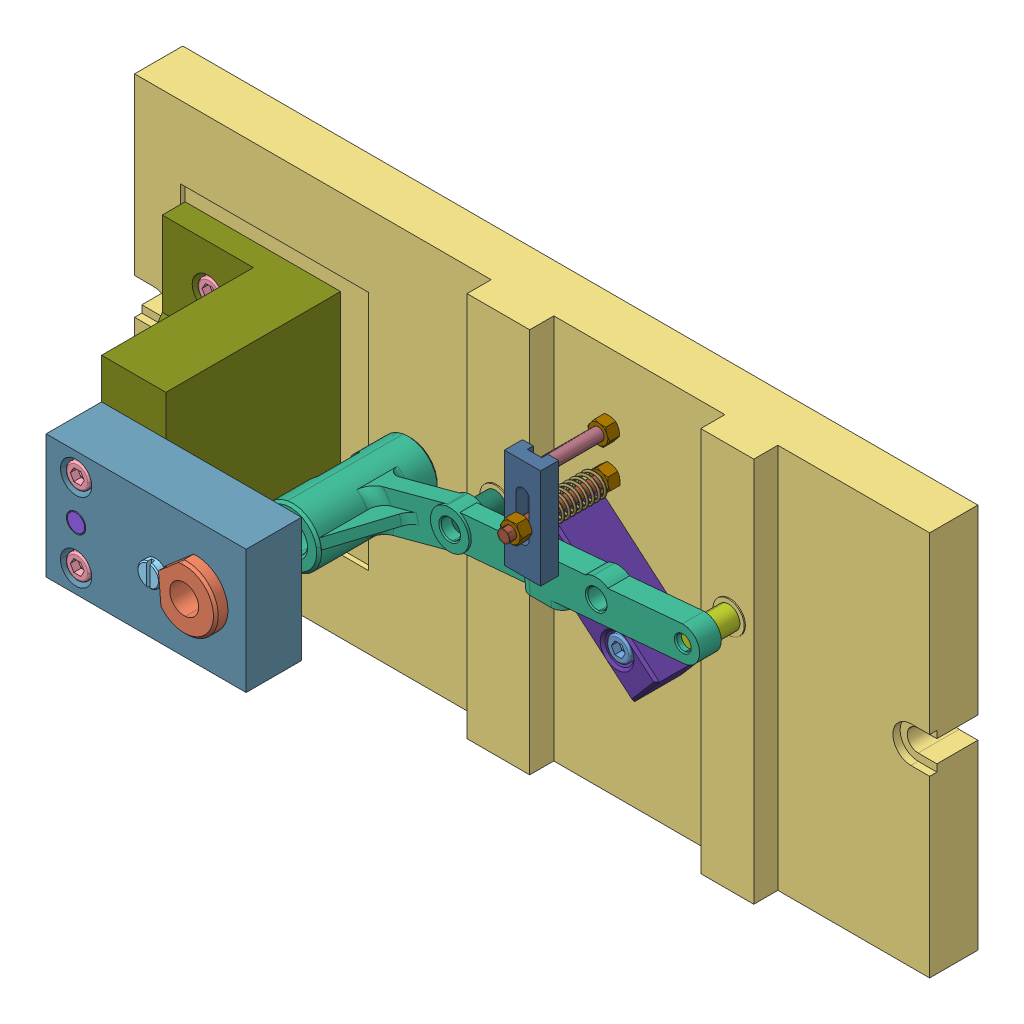
SolidWorks assembly jiajuzhuangpeitu_stp, configuration 默认. Lengths in mm.
Overall size (330 160 122.5).
25 component instances, 17 part files, 0 mates.
Components (placement in the parent):
- jiajuzhuangpeitu_stp.prt-1: jiajuzhuangpeitu_stp.prt [默认] at origin size (330 160 122.5)
  - hexagon socket head cap screws gb_GB_FASTENER_SCREWS_HSHCS M6X16-N.prt-1: hexagon socket head cap screws gb_GB_FASTENER_SCREWS_HSHCS M6X16-N.prt [默认] at (32.9073 12.8086 40) x (0 0 -1) z (1 0 0) size (22 10 10)
  - zuantao.prt-1: zuantao.prt [默认] at (-45.9116 0 98.5) x (-0.996497 -0.083623 0) z (-0.083623 0.996497 0) size (26.3 28 26.3)
  - jiajuti.prt-1: jiajuti.prt [默认] at origin size (330 160 30.5)
  - hexagon socket head cap screws gb_GB_FASTENER_SCREWS_HSHCS M6X25-N.prt-1: hexagon socket head cap screws gb_GB_FASTENER_SCREWS_HSHCS M6X25-N.prt [默认] at (-95.7787 16.3213 113) x (0 0 -1) z (1 0 0) size (31 10 10)
  - zuantaoluos.prt-1: zuantaoluos.prt [默认] at (-61.8248 -0.0368 99.5) x (1 0 0) z (0 -1 0) size (9.5 18 9.5)
  - gongjian.prt-1: gongjian.prt [默认] at (-747.1169 -114.2723 -31.3393) x (0.985408 0.170209 0) z (0.170209 -0.985408 0) size (158.09 50 24.28)
  - hexagon socket head cap screws gb_GB_FASTENER_SCREWS_HSHCS M6X25-N.prt-2: hexagon socket head cap screws gb_GB_FASTENER_SCREWS_HSHCS M6X25-N.prt [默认] at (-127.1019 -23.8797 27) x (0 0 -1) z (1 0 0) size (31 10 10)
  - lingxingxiao.prt-1: lingxingxiao.prt [默认] at (92.0417 18.5033 24.6342) x (-0.923728 -0.383049 0) z (-0.383049 0.923728 0) size (9.38 22.39 9.38)
  - parallel pins hardening steel gb_GB_CONNECTING_PIECE_PIN_DP 8X30.prt-1: parallel pins hardening steel gb_GB_CONNECTING_PIECE_PIN_DP 8X30.prt [默认] at (-95.7787 0 83.5) x (0 0 1) z (-1 0 0) size (30 8 8)
  - NONE20595.prt-1: NONE20595.prt [默认] at (39.8822 -58.7176 2.0546) x (-1 0 0) z (0 0 -1) size (15.26 41.44 57.36)
    - _X2_87BA6BCD_X0_ GB_T 41-2000 M 10.prt-1: _X2_87BA6BCD_X0_ GB_T 41-2000 M 10.prt [默认] at (7.1247 93.6462 -62.0704) x (0 0 1) z (0 1 0) size (4.75 9.24 8)
    - NONE6417.prt-1: NONE6417.prt [默认] at (43.3747 -36.1491 -43.4166) x (1 0 0) z (0 0 -1) size (15 41.44 7.5)
    - _X2_87BA6BCD_X0_ GB_T 41-2000 M 10.prt-2: _X2_87BA6BCD_X0_ GB_T 41-2000 M 10.prt [默认] at (7.1247 93.6462 -25.4265) x (0 0 1) z (-0.978146 0.207917 0) size (4.75 9.24 8)
    - _X2_87BA67F1_X0_ GB_T 901-1988 M10x180.prt-1: _X2_87BA67F1_X0_ GB_T 901-1988 M10x180.prt [默认] at (7.1247 93.6462 -58.0326) x (0 0 1) z (-0.703647 0.71055 0) size (56.97 5 5)
    - _X2_87BA6BCD_X0_ GB_T 41-2000 M 10.prt-3: _X2_87BA6BCD_X0_ GB_T 41-2000 M 10.prt [默认] at (7.3747 110.6454 -15.9265) x (0 0 -1) z (-0.139431 0.990232 0) size (4.75 9.24 8)
    - NONE.prt-1: NONE.prt [默认] at (7.1247 93.6462 70.3443) x (-0.71055 -0.703647 0) z (0 0 -1) size (10.63 10.61 21.32)
    - _X2_87BA9489_X0_ GB_T 878-2007 10x35.prt-1: _X2_87BA9489_X0_ GB_T 878-2007 10x35.prt [默认] at (7.3747 110.6454 76.5602) x (0 0 1) z (0.00668 0.999978 0) size (44.79 5 5)
  - zuanmoban.prt-1: zuanmoban.prt [默认] at (-66.7 0 113.5) size (83 51.5 23)
  - hexagon socket head cap screws gb_GB_FASTENER_SCREWS_HSHCS M6X25-N.prt-3: hexagon socket head cap screws gb_GB_FASTENER_SCREWS_HSHCS M6X25-N.prt [默认] at (-127.1019 23.8797 27) x (0 0 -1) z (1 0 0) size (31 10 10)
  - yuanzhuxiao.prt-1: yuanzhuxiao.prt [默认] at (-4.7169 11.0381 45.4075) x (0.689799 0.724 0) z (-0.724 0.689799 0) size (9.38 22.39 9.38)
  - hexagon socket head cap screws gb_GB_FASTENER_SCREWS_HSHCS M6X16-N.prt-2: hexagon socket head cap screws gb_GB_FASTENER_SCREWS_HSHCS M6X16-N.prt [默认] at (55.7561 -6.6319 40) x (0 0 -1) z (1 0 0) size (22 10 10)
  - zuanmobanzhijia.prt-1: zuanmobanzhijia.prt [默认] at (-81.5 0 18) x (1 0 0) z (0 -1 0) size (64.5 72.5 85)
  - hexagon socket head cap screws gb_GB_FASTENER_SCREWS_HSHCS M6X25-N.prt-4: hexagon socket head cap screws gb_GB_FASTENER_SCREWS_HSHCS M6X25-N.prt [默认] at (-95.7787 -16.3213 113) x (0 0 -1) z (1 0 0) size (31 10 10)
  - dianban.prt-1: dianban.prt [默认] at (44.3317 3.0883 30.25) x (0.648015 0.761628 0) z (0.761628 -0.648015 0) size (16 20.5 60)
